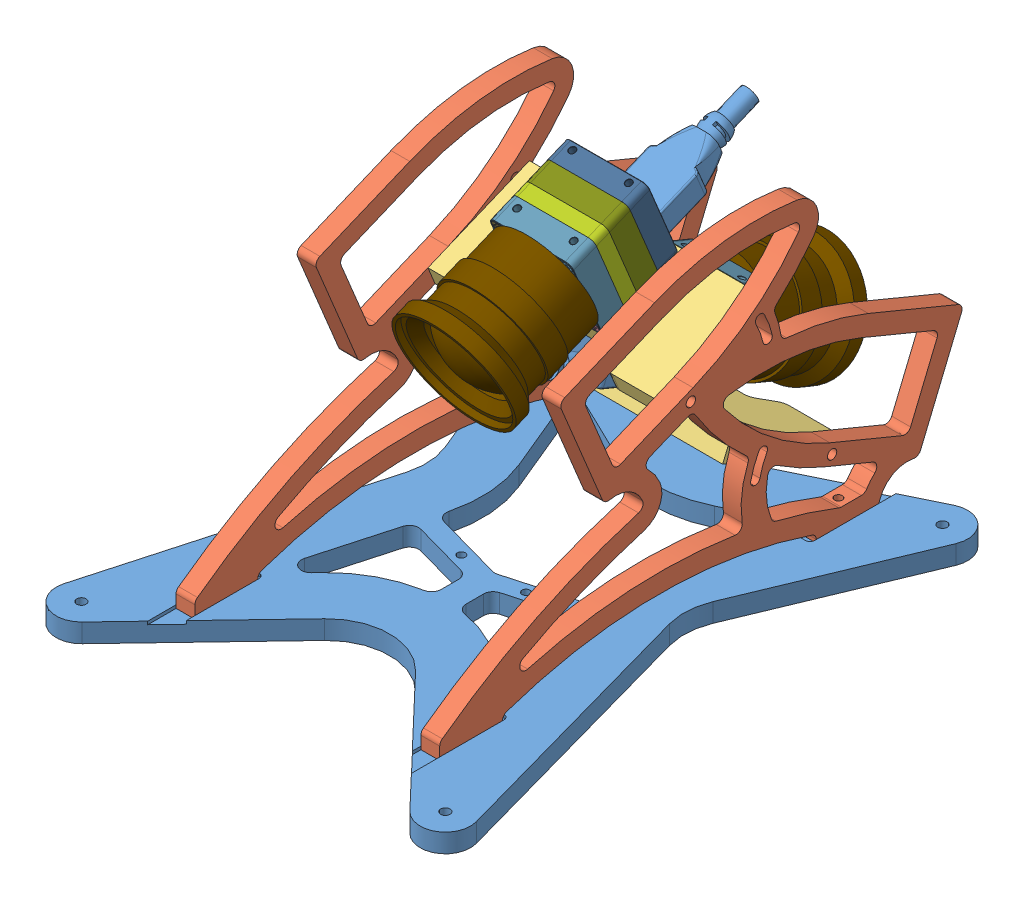
SolidWorks assembly visionmod, configuration Default. Lengths in mm.
Overall size (131.97 125.42 188.96).
77 component instances, 37 part files, 19 mates.
Components (placement in the parent):
- xiq_mount_base-1: xiq_mount_base [Default] at (-42.942 -6.0804 24.0733) size (131.97 6 174.39)
- xiq_mount_small2-1: xiq_mount_small2 [Default] at (-84.942 -1.0804 89.0733) size (6 98.66 166.42)
- xiq_mount_small2-2: xiq_mount_small2 [Default] at (-6.942 -1.0804 89.0733) size (6 98.66 166.42)
- xiq_mount-1: xiq_mount [Default] at (-78.942 53.2346 12.5446) x (1 0 0) z (0 -0.382683 0.92388) size (72 6 35)
- xiq_mount-2: xiq_mount [Default] at (-6.942 16.2346 -39.3981) x (-1 0 0) z (0 -0.382683 -0.92388) size (72 6 35)
- xiq_asm-1: xiq_asm [Default] at (2.0688 61.4566 8.3736) x (1 0 0) z (0 -0.382683 0.92388) size (43.42 43.42 98.47)
  - MQ013-E2-3: MQ013-E2 [Default] at (-45.0108 13.2 -18.97) x (1 0 0) z (0 0 -1) size (26.4 26.4 26.52)
    - 1-1: 1 [Default] at origin size (3 3 14.55)
    - 2-1: 2 [Default] at origin size (12.7 12.7 2.5)
    - 3-1: 3 [Default] at origin size (0.4 1.86 4.35)
    - 4-1: 4 [Default] at origin size (0.4 1.86 4.35)
    - 5-1: 5 [Default] at origin size (0.4 1.86 4.35)
    - 6-1: 6 [Default] at origin size (0.4 1.86 4.35)
    - 7-1: 7 [Default] at origin size (0.4 1.86 4.35)
    - 8-1: 8 [Default] at origin size (0.4 1.86 4.35)
    - 9-1: 9 [Default] at origin size (12.6 2.26 5)
    - 10-1: 10 [Default] at origin size (13.72 2.97 5.35)
    - 11-1: 11 [Default] at origin size (0.4 1.86 4.35)
    - 12-1: 12 [Default] at origin size (0.4 1.86 4.35)
    - 13-1: 13 [Default] at origin size (0.4 1.86 4.35)
    - 14-1: 14 [Default] at origin size (0.4 1.86 4.35)
    - 15-1: 15 [Default] at origin size (5 5 6)
    - 16-1: 16 [Default] at origin size (4 4 6.3)
    - 17-1: 17 [Default] at origin size (0.37 0.37 0.6)
    - 18-1: 18 [Default] at origin size (1.6 1.6 5.8)
    - 19-1: 19 [Default] at origin size (3 3 10.55)
    - 20-1: 20 [Default] at origin size (3 3 14.55)
    - 21-1: 21 [Default] at origin size (25.1 25.1 1.1)
    - 22-1: 22 [Default] at origin size (26.4 26.4 5)
    - 23-1: 23 [Default] at origin size (1.6 1.6 5.8)
    - 24-1: 24 [Default] at origin size (3 3 10.55)
    - 25-1: 25 [Default] at origin size (26.4 26.4 6.8)
    - 26-1: 26 [Default] at origin size (1.6 1.6 5.8)
    - 27-1: 27 [Default] at origin size (3 3 14.55)
    - 28-1: 28 [Default] at origin size (3 3 10.55)
    - 29-1: 29 [Default] at origin size (26.4 26.4 8)
    - 30-1: 30 [Default] at origin size (3 3 14.55)
    - 31-1: 31 [Default] at origin size (26.4 26.4 7.67)
    - 32-1: 32 [Default] at origin size (3 3 10.55)
  - tamron_22HA-1: tamron_22HA [Default] at (-45.0108 13.2 -5) x (-0.192132 0.981369 0) z (0 0 1) size (37 37 36.5)
  - micro_usb3_05-1: micro_usb3_05 [Default] at (-51.1461 3.7948 -26.47) size (15.6 9.42 46.1)
- xiq_asm-2: xiq_asm [Default] at (-87.9528 24.4566 -35.227) x (-1 0 0) z (0 -0.382683 -0.92388) size (43.42 43.42 98.47)
  - MQ013-E2-3: MQ013-E2 [Default] at (-45.0108 13.2 -18.97) x (1 0 0) z (0 0 -1) size (26.4 26.4 26.52)
    - 1-1: 1 [Default] at origin size (3 3 14.55)
    - 2-1: 2 [Default] at origin size (12.7 12.7 2.5)
    - 3-1: 3 [Default] at origin size (0.4 1.86 4.35)
    - 4-1: 4 [Default] at origin size (0.4 1.86 4.35)
    - 5-1: 5 [Default] at origin size (0.4 1.86 4.35)
    - 6-1: 6 [Default] at origin size (0.4 1.86 4.35)
    - 7-1: 7 [Default] at origin size (0.4 1.86 4.35)
    - 8-1: 8 [Default] at origin size (0.4 1.86 4.35)
    - 9-1: 9 [Default] at origin size (12.6 2.26 5)
    - 10-1: 10 [Default] at origin size (13.72 2.97 5.35)
    - 11-1: 11 [Default] at origin size (0.4 1.86 4.35)
    - 12-1: 12 [Default] at origin size (0.4 1.86 4.35)
    - 13-1: 13 [Default] at origin size (0.4 1.86 4.35)
    - 14-1: 14 [Default] at origin size (0.4 1.86 4.35)
    - 15-1: 15 [Default] at origin size (5 5 6)
    - 16-1: 16 [Default] at origin size (4 4 6.3)
    - 17-1: 17 [Default] at origin size (0.37 0.37 0.6)
    - 18-1: 18 [Default] at origin size (1.6 1.6 5.8)
    - 19-1: 19 [Default] at origin size (3 3 10.55)
    - 20-1: 20 [Default] at origin size (3 3 14.55)
    - 21-1: 21 [Default] at origin size (25.1 25.1 1.1)
    - 22-1: 22 [Default] at origin size (26.4 26.4 5)
    - 23-1: 23 [Default] at origin size (1.6 1.6 5.8)
    - 24-1: 24 [Default] at origin size (3 3 10.55)
    - 25-1: 25 [Default] at origin size (26.4 26.4 6.8)
    - 26-1: 26 [Default] at origin size (1.6 1.6 5.8)
    - 27-1: 27 [Default] at origin size (3 3 14.55)
    - 28-1: 28 [Default] at origin size (3 3 10.55)
    - 29-1: 29 [Default] at origin size (26.4 26.4 8)
    - 30-1: 30 [Default] at origin size (3 3 14.55)
    - 31-1: 31 [Default] at origin size (26.4 26.4 7.67)
    - 32-1: 32 [Default] at origin size (3 3 10.55)
  - tamron_22HA-1: tamron_22HA [Default] at (-45.0108 13.2 -5) x (-0.192132 0.981369 0) z (0 0 1) size (37 37 36.5)
  - micro_usb3_05-1: micro_usb3_05 [Default] at (-51.1461 3.7948 -26.47) size (15.6 9.42 46.1)
Mates (geometry in assembly coordinates):
- Coincident1: coincident anti-aligned: plane of xiq_mount_base-1 through (-42.942 -1.0804 24.0733) normal (0 1 0); plane of xiq_mount_small2-1 through (-78.942 -1.0804 89.0733) normal (0 -1 0)
- Concentric1: concentric aligned: cylinder of xiq_mount_base-1 through (-81.942 -0.0804 79.0733) axis (0 -1 0) radius 1.5; cylinder of xiq_mount_small2-1 through (-81.942 -1.0804 79.0733) axis (0 -1 0) radius 1.25
- Concentric2: concentric aligned: cylinder of xiq_mount_base-1 through (-81.942 -0.0804 -40.9267) axis (0 -1 0) radius 1.5; cylinder of xiq_mount_small2-1 through (-81.942 -1.0804 -40.9267) axis (0 -1 0) radius 1.25
- Coincident2: coincident anti-aligned: plane of xiq_mount_base-1 through (-42.942 -1.0804 24.0733) normal (0 1 0); plane of xiq_mount_small2-2 through (-0.942 -1.0804 89.0733) normal (0 -1 0)
- Concentric3: concentric aligned: cylinder of xiq_mount_base-1 through (-3.942 -0.0804 79.0733) axis (0 -1 0) radius 1.5; cylinder of xiq_mount_small2-2 through (-3.942 -1.0804 79.0733) axis (0 -1 0) radius 1.25
- Concentric4: concentric aligned: cylinder of xiq_mount_base-1 through (-3.942 -0.0804 -40.9267) axis (0 -1 0) radius 1.5; cylinder of xiq_mount_small2-2 through (-3.942 -1.0804 -40.9267) axis (0 -1 0) radius 1.25
- Concentric5: concentric anti-aligned: cylinder of xiq_mount_small2-2 through (-0.942 57.9196 9.0733) axis (-1 0 0) radius 1.5; cylinder of xiq_mount-1 through (-6.942 57.9196 9.0733) axis (1 0 0) radius 1.25
- Coincident3: coincident anti-aligned: plane of xiq_mount_small2-2 through (-6.942 -0.0804 67.0733) normal (-1 0 0); plane of xiq_mount-1 through (-6.942 58.7779 14.8407) normal (1 0 0)
- Concentric6: concentric aligned: cylinder of xiq_mount_small2-1 through (-78.942 20.9196 -35.9267) axis (-1 0 0) radius 1.5; cylinder of xiq_mount-2 through (-78.942 20.9196 -35.9267) axis (-1 0 0) radius 1.25
- Coincident5: coincident anti-aligned: plane of xiq_mount_small2-1 through (-78.942 -0.0804 67.0733) normal (1 0 0); plane of xiq_mount-2 through (-78.942 21.7779 -41.6942) normal (-1 0 0)
- Angle1: planar angle = 0.392699 rad anti-aligned: plane of xiq_mount-2 through (-6.942 16.2346 -39.3981) normal (0 -0.92388 0.382683); plane of xiq_mount_base-1 through (-100.9248 -0.0804 -55.1227) normal (0 1 0)
- Angle2: planar angle = 0.392699 rad anti-aligned: plane of xiq_mount-1 through (-78.942 53.2346 12.5446) normal (0 -0.92388 -0.382683); plane of xiq_mount_base-1 through (-100.9248 -0.0804 -55.1227) normal (0 1 0)
- Concentric7: concentric anti-aligned: cylinder of xiq_mount-1 through (-51.942 58.0172 0.9958) axis (0 0.92388 0.382683) radius 1; cylinder of xiq_asm-1/MQ013-E2-3/29-1 through (-51.942 66.333 4.4403) axis (0 -0.92388 -0.382683) radius 1
- Concentric8: concentric anti-aligned: cylinder of xiq_mount-1 through (-33.942 58.0172 0.9958) axis (0 0.92388 0.382683) radius 1; cylinder of xiq_asm-1/MQ013-E2-3/29-1 through (-33.942 66.333 4.4403) axis (0 -0.92388 -0.382683) radius 1
- Coincident8: coincident anti-aligned: plane of xiq_mount-1 through (-78.942 58.7779 14.8407) normal (0 0.92388 0.382683); plane of xiq_asm-1/MQ013-E2-3/25-1 through (-29.742 71.5863 -16.0815) normal (0 -0.92388 -0.382683)
- Concentric9: concentric anti-aligned: cylinder of xiq_mount-2 through (-33.942 21.0172 -27.8492) axis (0 0.92388 -0.382683) radius 1; cylinder of xiq_asm-2/MQ013-E2-3/29-1 through (-33.942 29.333 -31.2937) axis (0 -0.92388 0.382683) radius 1
- Concentric10: concentric anti-aligned: cylinder of xiq_mount-2 through (-51.942 21.0172 -27.8492) axis (0 0.92388 -0.382683) radius 1; cylinder of xiq_asm-2/MQ013-E2-3/29-1 through (-51.942 29.333 -31.2937) axis (0 -0.92388 0.382683) radius 1
- Coincident9: coincident anti-aligned: plane of xiq_mount-2 through (-6.942 21.7779 -41.6942) normal (0 0.92388 -0.382683); plane of xiq_asm-2/MQ013-E2-3/29-1 through (-56.142 27.5181 -27.836) normal (0 -0.92388 0.382683)
- Concentric11: concentric anti-aligned: cylinder of xiq_mount-1 through (-33.942 58.0172 0.9958) axis (0 0.92388 0.382683) radius 1; cylinder of xiq_asm-1/MQ013-E2-3/29-1 through (-33.942 66.333 4.4403) axis (0 -0.92388 -0.382683) radius 1
